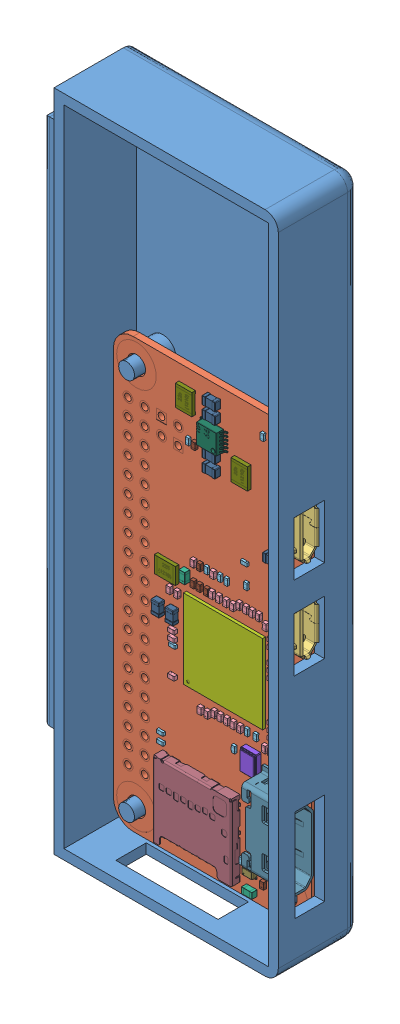
SolidWorks assembly AssemblageSwitchFinalCaseRpi, configuration Défaut. Lengths in mm.
Overall size (36.7 100.65 12.5).
84 component instances, 16 part files, 3 mates.
Components (placement in the parent):
- Assemblage_RASP_switch_case-1: Assemblage_RASP_switch_case [Défaut] at origin size (36.7 100.65 12.5)
  - joycon_rasp-1: joycon_rasp [Défaut] at (-68.0773 -55.2261 -6.25) size (36.7 100.65 12.5)
- RapberryPiZero-1: RapberryPiZero [Default] at (-64.1315 30.5303 -21.8466) x (0 1 0) z (1 0 0) size (65 4.45 31.23)
  - Raspberry_pizero_PCB-1: Raspberry_pizero_PCB [Default] at (-51.2564 20.0966 13.0542) size (65 1 30)
  - Micro USB_input_female (short)-SMT-1: Micro USB_input_female (short)-SMT [Default] at (-42.3564 22.3216 26.5042) size (7.98 2.94 5.43)
  - Micro USB_input_female (short)-SMT-2: Micro USB_input_female (short)-SMT [Default] at (-29.7564 22.3216 26.5042) size (7.98 2.94 5.43)
  - 0204 - Capacitor-1: 0204 - Capacitor [Default] at (-62.4121 21.3466 11.2398) size (1 0.5 0.6)
  - 0204 - Capacitor-2: 0204 - Capacitor [Default] at (-62.4121 21.3466 12.2528) size (1 0.5 0.6)
  - 0204 - Capacitor-3: 0204 - Capacitor [Default] at (-61.8122 21.3466 13.3136) size (1 0.5 0.6)
  - 0204 - Capacitor-4: 0204 - Capacitor [Default] at (-61.8122 21.3466 14.2646) size (1 0.5 0.6)
  - 0204 - Capacitor-5: 0204 - Capacitor [Default] at (-61.8122 21.3466 15.241) size (1 0.5 0.6)
  - 0204 - Capacitor-6: 0204 - Capacitor [Default] at (-61.8122 21.3466 16.2144) size (1 0.5 0.6)
  - 0204 - Capacitor-7: 0204 - Capacitor [Default] at (-61.8122 21.3466 17.2416) size (1 0.5 0.6)
  - 0204 - Capacitor-8: 0204 - Capacitor [Default] at (-62.5919 21.3466 20.9695) size (1 0.5 0.6)
  - 0204 - Capacitor-9: 0204 - Capacitor [Default] at (-62.5919 21.3466 21.919) size (1 0.5 0.6)
  - 0204 - Capacitor-10: 0204 - Capacitor [Default] at (-60.4584 21.3466 22.3712) x (0 0 1) z (-1 0 0) size (1 0.5 0.6)
  - 0204 - Capacitor-11: 0204 - Capacitor [Default] at (-60.0807 21.3466 22.3712) x (0 0 -1) z (1 0 0) size (1 0.5 0.6)
  - 0204 - Capacitor-12: 0204 - Capacitor [Default] at (-59.0466 21.3466 22.3712) x (0 0 -1) z (1 0 0) size (1 0.5 0.6)
  - 0204 - Capacitor-13: 0204 - Capacitor [Default] at (-52.6496 21.3466 22.316) x (0 0 1) z (-1 0 0) size (1 0.5 0.6)
  - 0204 - Capacitor-14: 0204 - Capacitor [Default] at (-52.25 21.3466 22.316) x (0 0 -1) z (1 0 0) size (1 0.5 0.6)
  - 0204 - Capacitor-15: 0204 - Capacitor [Default] at (-51.2398 21.3466 22.316) x (0 0 -1) z (1 0 0) size (1 0.5 0.6)
  - 0204 - Capacitor-16: 0204 - Capacitor [Default] at (-49.1841 21.3466 22.316) x (0 0 -1) z (1 0 0) size (1 0.5 0.6)
  - 0204 - Capacitor-17: 0204 - Capacitor [Default] at (-48.1448 21.3466 22.316) x (0 0 -1) z (1 0 0) size (1 0.5 0.6)
  - 0204 - Capacitor-18: 0204 - Capacitor [Default] at (-46.475 21.3466 21.113) size (1 0.5 0.6)
  - 0204 - Capacitor-19: 0204 - Capacitor [Default] at (-45.7322 21.3466 20.0663) size (1 0.5 0.6)
  - 0204 - Capacitor-20: 0204 - Capacitor [Default] at (-45.7322 21.3466 19.0675) size (1 0.5 0.6)
  - 0204 - Capacitor-21: 0204 - Capacitor [Default] at (-45.7322 21.3466 18.1249) size (1 0.5 0.6)
  - 0204 - Capacitor-22: 0204 - Capacitor [Default] at (-45.7322 21.3466 17.1095) size (1 0.5 0.6)
  - 0204 - Capacitor-23: 0204 - Capacitor [Default] at (-46.3457 21.3466 16.1412) size (1 0.5 0.6)
  - 0204 - Capacitor-24: 0204 - Capacitor [Default] at (-46.3457 21.3466 15.1229) size (1 0.5 0.6)
  - 0204 - Capacitor-25: 0204 - Capacitor [Default] at (-46.3457 21.3466 14.0197) size (1 0.5 0.6)
  - 0204 - Capacitor-26: 0204 - Capacitor [Default] at (-46.3457 21.3466 12.9589) size (1 0.5 0.6)
  - 0204 - Capacitor-27: 0204 - Capacitor [Default] at (-43.6156 21.3466 13.1418) size (1 0.5 0.6)
  - 0204 - Capacitor-28: 0204 - Capacitor [Default] at (-43.6156 21.3466 10.1424) size (1 0.5 0.6)
  - 0204 - Capacitor-29: 0204 - Capacitor [Default] at (-48.9117 21.3466 7.6917) size (1 0.5 0.6)
  - 0204 - Capacitor-30: 0204 - Capacitor [Default] at (-55.4926 21.3466 7.2526) x (0 0 -1) z (1 0 0) size (1 0.5 0.6)
  - 0204 - Capacitor-31: 0204 - Capacitor [Default] at (-53.7932 21.3466 7.2526) x (0 0 1) z (-1 0 0) size (1 0.5 0.6)
  - 0204 - Capacitor-32: 0204 - Capacitor [Default] at (-59.8477 21.3466 7.2526) x (0 0 1) z (-1 0 0) size (1 0.5 0.6)
  - 0204- Resistor-15: 0204- Resistor [Default] at (-43.6109 21.4522 15.4193) x (-1 0 0) z (0 -1 0) size (0.99 0.51 0.36)
  - 0204- Resistor-14: 0204- Resistor [Default] at (-43.6109 21.4522 14.4127) x (-1 0 0) z (0 -1 0) size (0.99 0.51 0.36)
  - 0204- Resistor-13: 0204- Resistor [Default] at (-43.6109 21.4522 12.4047) x (-1 0 0) z (0 -1 0) size (0.99 0.51 0.36)
  - 0204- Resistor-4: 0204- Resistor [Default] at (-42.6936 21.4522 18.4076) x (-1 0 0) z (0 -1 0) size (0.99 0.51 0.36)
  - 0204- Resistor-5: 0204- Resistor [Default] at (-39.831 21.4522 18.1462) x (0 0 1) z (0 -1 0) size (0.99 0.51 0.36)
  - 0204- Resistor-7: 0204- Resistor [Default] at (-61.8169 21.4522 19.8533) x (-1 0 0) z (0 -1 0) size (0.99 0.51 0.36)
  - 0204- Resistor-8: 0204- Resistor [Default] at (-61.8169 21.4522 18.5178) x (-1 0 0) z (0 -1 0) size (0.99 0.51 0.36)
  - 0204- Resistor-9: 0204- Resistor [Default] at (-79.148 21.4522 17.7279) x (-1 0 0) z (0 -1 0) size (0.99 0.51 0.36)
  - 0204- Resistor-10: 0204- Resistor [Default] at (-56.0985 21.4522 7.2479) x (0 0 -1) z (0 -1 0) size (0.99 0.51 0.36)
  - 0204- Resistor-11: 0204- Resistor [Default] at (-28.0827 21.4522 9.5819) x (-1 0 0) z (0 -1 0) size (0.99 0.51 0.36)
  - 0204- Resistor-12: 0204- Resistor [Default] at (-21.8613 21.4522 20.9026) x (-1 0 0) z (0 -1 0) size (0.99 0.51 0.36)
  - CAP-0306-1: CAP-0306 [Default] at (-45.8903 21.4966 8.7634) size (1.6 0.8 0.9)
  - CAP-0306-2: CAP-0306 [Default] at (-82.0031 21.4966 19.0464) x (0 0 1) z (-1 0 0) size (1.6 0.8 0.9)
  - Raspberry_pizero_BCM2835 with VC4-2: Raspberry_pizero_BCM2835 with VC4 [Default] at (-54.1608 21.5466 15.1238) x (1 0 0) z (0 0 -1) size (12 0.65 12)
  - Crystal 3.4x2.4mm-1: Crystal 3.4x2.4mm [Default] at (-65.3089 21.0966 19.2633) size (3.2 1 2.4)
  - 0204- Resistor-16: 0204- Resistor [Default] at (-68.4329 21.4522 5.4384) x (0 0 1) z (0 -1 0) size (0.99 0.51 0.36)
  - 0204- Resistor-17: 0204- Resistor [Default] at (-69.7255 21.4522 5.4384) x (0 0 1) z (0 -1 0) size (0.99 0.51 0.36)
  - 0204- Resistor-18: 0204- Resistor [Default] at (-65.0626 21.4522 16.5355) x (1 0 0) z (0 -1 0) size (0.99 0.51 0.36)
  - 32,768 Khz Crystal-1: 32,768 Khz Crystal [Default] at (-60.5154 21.1428 26.5473) x (0.999848 -0.017452 0) z (0 0 1) size (3.4 1.03 1.5)
  - 0805- Capacitor-1: 0805- Capacitor [Default] at (-51.9496 21.9966 5.2384) x (1 0 0) z (0 -1 0) size (2 1.25 0.9)
  - 0805- Capacitor-2: 0805- Capacitor [Default] at (-51.9496 21.9966 7.3589) x (1 0 0) z (0 -1 0) size (2 1.25 0.9)
  - 0805- Capacitor-3: 0805- Capacitor [Default] at (-37.009 21.9966 22.5384) x (0 0 -1) z (0 -1 0) size (2 1.25 0.9)
  - 0805- Capacitor-4: 0805- Capacitor [Default] at (-29.8247 21.9966 13.3538) x (0 0 1) z (0 -1 0) size (2 1.25 0.9)
  - 0805- Capacitor-5: 0805- Capacitor [Default] at (-27.9052 21.9966 13.3538) x (0 0 -1) z (0 -1 0) size (2 1.25 0.9)
  - 0805- Capacitor-6: 0805- Capacitor [Default] at (-22.8003 21.9966 13.3538) x (0 0 -1) z (0 -1 0) size (2 1.25 0.9)
  - 0805- Capacitor-7: 0805- Capacitor [Default] at (-20.9924 21.9966 13.3538) x (0 0 -1) z (0 -1 0) size (2 1.25 0.9)
  - 0204- Resistor-19: 0204- Resistor [Default] at (-48.8769 21.4522 23.8207) x (1 0 0) z (0 -1 0) size (0.99 0.51 0.36)
  - 0204- Resistor-20: 0204- Resistor [Default] at (-52.4165 21.4522 24.0419) x (1 0 0) z (0 -1 0) size (0.99 0.51 0.36)
  - 0204 - Capacitor-33: 0204 - Capacitor [Default] at (-47.1199 21.3466 23.926) x (0 0 1) z (-1 0 0) size (1 0.5 0.6)
  - 0204 - Capacitor Brown-34: 0204 - Capacitor Brown [Default] at (-57.5817 21.3466 26.803) size (1 0.5 0.6)
  - 0204 - Capacitor Brown-35: 0204 - Capacitor Brown [Default] at (-64.0312 21.3466 26.8794) size (1 0.5 0.6)
  - 0204 - Capacitor Brown-36: 0204 - Capacitor Brown [Default] at (-46.3457 21.3466 12.214) size (1 0.5 0.6)
  - 0204 - Capacitor Brown-37: 0204 - Capacitor Brown [Default] at (-46.3457 21.3466 11.0963) size (1 0.5 0.6)
  - 0204 - Capacitor Brown-38: 0204 - Capacitor Brown [Default] at (-46.3457 21.3466 10.1566) size (1 0.5 0.6)
  - 0204 - Capacitor Brown-39: 0204 - Capacitor Brown [Default] at (-43.6156 21.3466 11.1151) size (1 0.5 0.6)
  - 0204 - Capacitor Brown-40: 0204 - Capacitor Brown [Default] at (-28.0874 21.3466 10.3236) size (1 0.5 0.6)
  - 0204 - Capacitor Brown-41: 0204 - Capacitor Brown [Default] at (-80.6197 21.3466 20.6997) size (1 0.5 0.6)
  - 0204- Resistor-21: 0204- Resistor [Default] at (-78.9105 21.4522 21.1554) x (1 0 0) z (0 -1 0) size (0.99 0.51 0.36)
  - 6-Pin SOT-1: 6-Pin SOT [Default] at (-79.714 21.0966 19.2138) x (0 0 1) z (0 1 0) size (1.5 1.84 0.95)
  - micro sd molex-1: micro sd molex [Default] at (-74.7768 21.6766 -33.0961) x (0 0 1) z (0 1 0) size (11.95 11.4 1.45)
  - hdmi type C-1: hdmi type C [Default] at (-71.3564 22.9466 28.6542) size (12.9 4.05 7.7)
  - Voltage Regulator 3x3mm 12-Pin-1: Voltage Regulator 3x3mm 12-Pin [Default] at (-23.6842 21.0966 12.6105) x (1 0 0) z (0 1 0) size (3 4.1 1.2)
  - 1210 inductor-1: 1210 inductor [Default] at (-46.4963 21.0916 6.3909) x (0 0 1) z (0 1 0) size (3.26 2.86 0.75)
  - 1210 inductor-2: 1210 inductor [Default] at (-22.7405 21.0916 9.2394) x (1 0 0) z (0 1 0) size (3.26 2.86 0.75)
  - 1210 inductor-3: 1210 inductor [Default] at (-28.2854 21.0916 17.6682) x (1 0 0) z (0 1 0) size (3.26 2.86 0.75)
  - 0204 - Capacitor-34: 0204 - Capacitor [Default] at (-48.9117 21.3466 6.5273) size (1 0.5 0.6)
Mates (geometry in assembly coordinates):
- Coaxiale1: concentric aligned: cylinder of Assemblage_RASP_switch_case-1/joycon_rasp-1 through (-39.5773 8.2739 0.75) axis (0 0 -1) radius 1.2; cylinder of RapberryPiZero-1/Raspberry_pizero_PCB-1 through (-39.5773 8.2739 -0.75) axis (0 0 -1) radius 1.375
- Coaxiale2: concentric aligned: cylinder of Assemblage_RASP_switch_case-1/joycon_rasp-1 through (-62.5773 -49.7261 0.75) axis (0 0 -1) radius 1.2; cylinder of RapberryPiZero-1/Raspberry_pizero_PCB-1 through (-62.5773 -49.7261 -0.75) axis (0 0 -1) radius 1.375
- Coïncidente1: coincident anti-aligned: plane of Assemblage_RASP_switch_case-1/joycon_rasp-1 through (-62.5773 8.2739 -1.75) normal (0 0 1); plane of RapberryPiZero-1/Raspberry_pizero_PCB-1 through (-62.5773 8.2739 -1.75) normal (0 0 -1)
